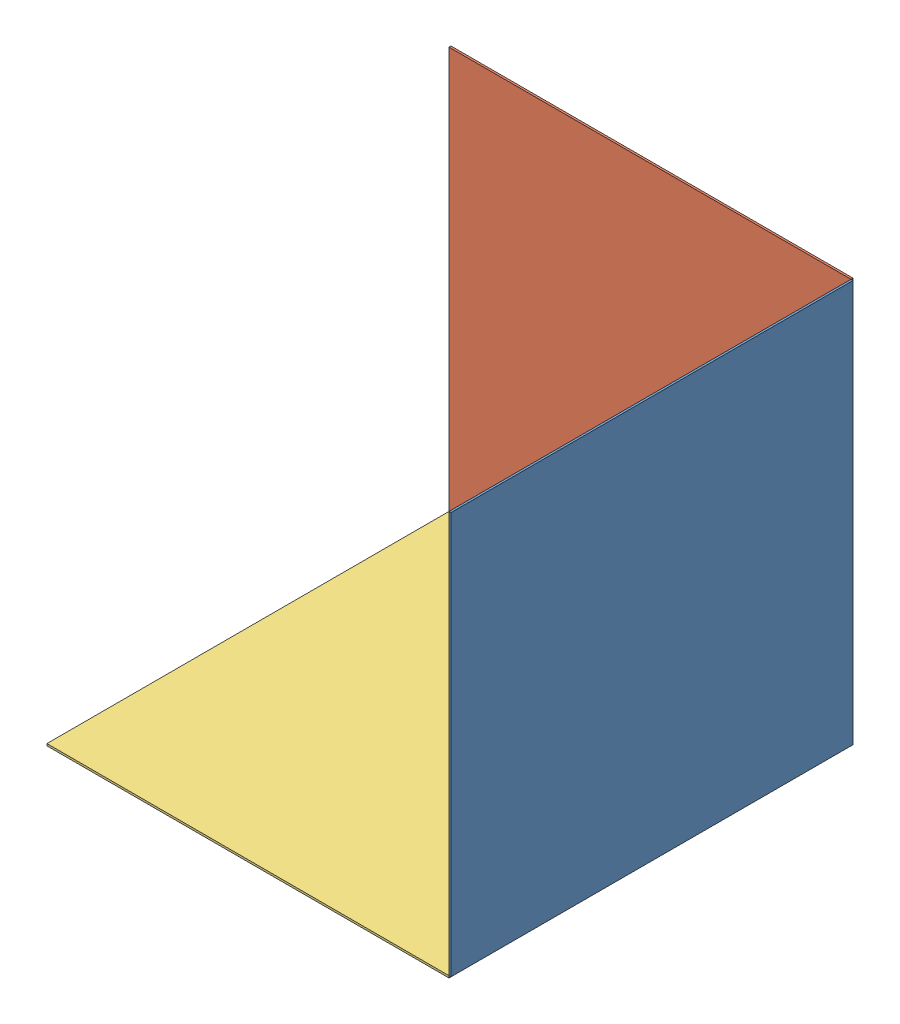
SolidWorks assembly 模型3, configuration 默认. Lengths in mm.
Overall size (201 201 201).
3 component instances, 3 part files, 6 mates.
Components (placement in the parent):
- 侧视图-1: 侧视图 [默认] at (0 100 100) size (1 200 200)
- 正视图-1: 正视图 [默认] at (-100 100 -1) size (200 200 1)
- 俯视图-1: 俯视图 [默认] at (-100 -1 100) size (200 1 200)
Mates (geometry in assembly coordinates):
- 重合1: coincident aligned: line of 侧视图-1 through (0 0 0) axis (0 1 0); line of 正视图-1 through (0 0 0) axis (0 1 0)
- 重合2: coincident: point of 侧视图-1; point of 正视图-1
- 重合3: coincident anti-aligned: line of 正视图-1 through (-200 0 0) axis (1 0 0); line of 俯视图-1 through (0 0 0) axis (-1 0 0)
- 重合4: coincident: point of 侧视图-1; point of 俯视图-1
- 重合5: coincident: line of 侧视图-1 through (0 0 200) axis (0 0 -1); line of 俯视图-1 through (0 0 200) axis (0 0 -1)
- 重合6: coincident: point of 侧视图-1; point of assembly
